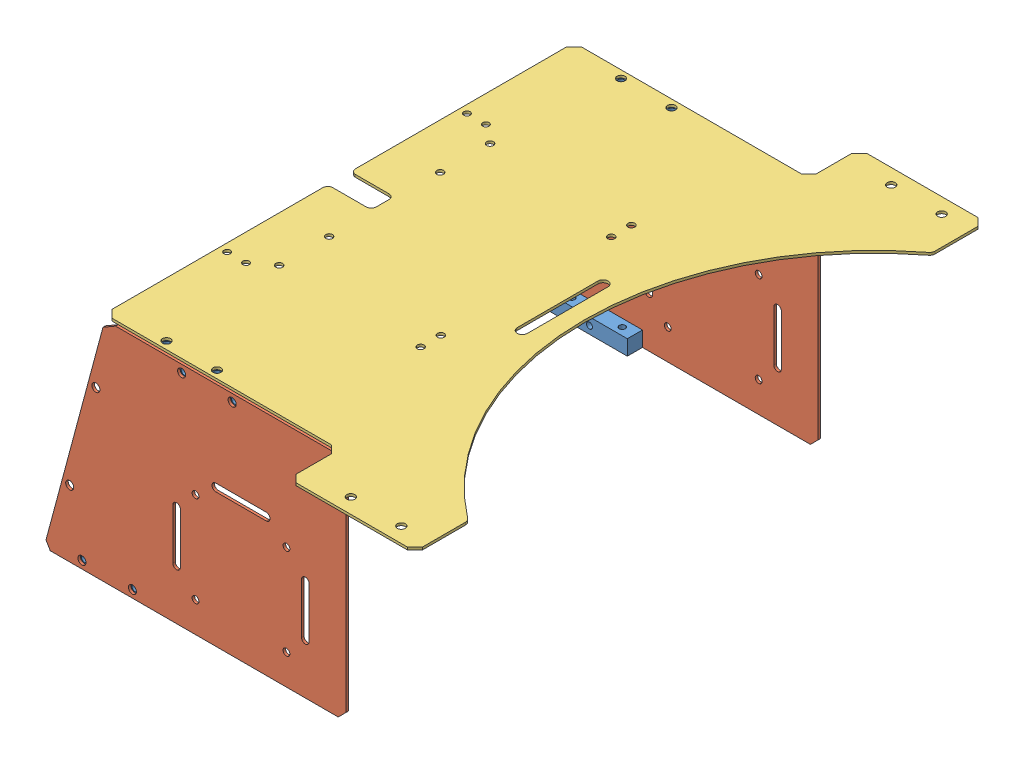
SolidWorks assembly 前部保护壳, configuration 默认. Lengths in mm.
Overall size (354.22 91 240).
7 component instances, 3 part files, 18 mates.
Components (placement in the parent):
- 转接件-4孔-1: 转接件-4孔 [默认] at (-31.4175 25.8402 45.7674) x (0 1 0) z (1 0 0) size (6 6 40)
- 转接件-4孔-2: 转接件-4孔 [默认] at (-31.4175 25.8402 -134.2326) x (0 1 0) z (1 0 0) size (6 6 40)
- 转接件-4孔-3: 转接件-4孔 [默认] at (-1.9175 109.8402 -128.2326) x (0 0 -1) z (1 0 0) size (6 6 40)
- 转接件-4孔-4: 转接件-4孔 [默认] at (-1.9175 109.8402 51.7674) x (0 0 -1) z (1 0 0) size (6 6 40)
- 侧面保护壳-1: 侧面保护壳 [默认] at (45.0825 18.3402 51.7674) x (0 0 1) z (-1 0 0) size (1 90 118.72)
- 侧面保护壳-2: 侧面保护壳 [默认] at (45.0825 18.3402 -135.2326) x (0 0 1) z (-1 0 0) size (1 90 118.72)
- 前上保护板-1: 前上保护板 [默认] at (38.4625 115.8402 -41.2326) x (0 0 -1) z (1 0 0) size (240 1 332.12)
Mates (geometry in assembly coordinates):
- 同心165: concentric anti-aligned: cylinder of 转接件-4孔-1 through (-26.4175 28.8402 1.7674) axis (0 0 1) radius 1.2; cylinder of 侧面保护壳-1 through (-26.4175 28.8402 52.7674) axis (0 0 -1) radius 1.6
- 同心166: concentric anti-aligned: cylinder of 转接件-4孔-1 through (-6.4175 28.8402 1.7674) axis (0 0 1) radius 1.2; cylinder of 侧面保护壳-1 through (-6.4175 28.8402 52.7674) axis (0 0 -1) radius 1.6
- 重合100: coincident anti-aligned: plane of 转接件-4孔-1 through (8.5825 25.8402 51.7674) normal (0 0 1); plane of 侧面保护壳-1 through (45.0825 18.3402 51.7674) normal (0 0 -1)
- 同心171: concentric anti-aligned: cylinder of 转接件-4孔-2 through (-26.4175 28.8402 -178.2326) axis (0 0 1) radius 1.2; cylinder of 侧面保护壳-2 through (-26.4175 28.8402 -134.2326) axis (0 0 -1) radius 1.6
- 同心172: concentric anti-aligned: cylinder of 转接件-4孔-2 through (-6.4175 28.8402 -178.2326) axis (0 0 1) radius 1.2; cylinder of 侧面保护壳-2 through (-6.4175 28.8402 -134.2326) axis (0 0 -1) radius 1.6
- 重合103: coincident anti-aligned: plane of 转接件-4孔-2 through (8.5825 25.8402 -134.2326) normal (0 0 -1); plane of 侧面保护壳-2 through (45.0825 18.3402 -134.2326) normal (0 0 1)
- 同心169: concentric anti-aligned: cylinder of 转接件-4孔-3 through (13.0825 112.8402 -178.2326) axis (0 0 1) radius 1.2; cylinder of 侧面保护壳-2 through (13.0825 112.8402 -134.2326) axis (0 0 -1) radius 1.6
- 同心170: concentric anti-aligned: cylinder of 转接件-4孔-3 through (33.0825 112.8402 -178.2326) axis (0 0 1) radius 1.2; cylinder of 侧面保护壳-2 through (33.0825 112.8402 -134.2326) axis (0 0 -1) radius 1.6
- 重合102: coincident anti-aligned: plane of 转接件-4孔-3 through (38.0825 109.8402 -134.2326) normal (0 0 -1); plane of 侧面保护壳-2 through (45.0825 18.3402 -134.2326) normal (0 0 1)
- 同心189: concentric aligned: cylinder of 转接件-4孔-3 through (23.0825 65.8402 -131.2326) axis (0 1 0) radius 1.2; cylinder of 前上保护板-1 through (23.0825 115.8402 -131.2326) axis (0 1 0) radius 1.6
- 同心190: concentric aligned: cylinder of 转接件-4孔-3 through (3.0825 65.8402 -131.2326) axis (0 1 0) radius 1.2; cylinder of 前上保护板-1 through (3.0825 115.8402 -131.2326) axis (0 1 0) radius 1.6
- 重合112: coincident anti-aligned: plane of 转接件-4孔-3 through (38.0825 115.8402 -128.2326) normal (0 1 0); plane of 前上保护板-1 through (38.4625 115.8402 -41.2326) normal (0 -1 0)
- 同心163: concentric anti-aligned: cylinder of 转接件-4孔-4 through (13.0825 112.8402 1.7674) axis (0 0 1) radius 1.2; cylinder of 侧面保护壳-1 through (13.0825 112.8402 52.7674) axis (0 0 -1) radius 1.6
- 同心164: concentric anti-aligned: cylinder of 转接件-4孔-4 through (33.0825 112.8402 1.7674) axis (0 0 1) radius 1.2; cylinder of 侧面保护壳-1 through (33.0825 112.8402 52.7674) axis (0 0 -1) radius 1.6
- 重合99: coincident anti-aligned: plane of 转接件-4孔-4 through (38.0825 109.8402 51.7674) normal (0 0 1); plane of 侧面保护壳-1 through (45.0825 18.3402 51.7674) normal (0 0 -1)
- 重合114: coincident anti-aligned: plane of 转接件-4孔-4 through (38.0825 115.8402 51.7674) normal (0 1 0); plane of 前上保护板-1 through (38.4625 115.8402 -41.2326) normal (0 -1 0)
- 同心193: concentric aligned: cylinder of 转接件-4孔-4 through (3.0825 65.8402 48.7674) axis (0 1 0) radius 1.2; circle of 前上保护板-1
- 同心194: concentric aligned: cylinder of 转接件-4孔-4 through (23.0825 65.8402 48.7674) axis (0 1 0) radius 1.2; cylinder of 前上保护板-1 through (23.0825 115.8402 48.7674) axis (0 1 0) radius 1.6
